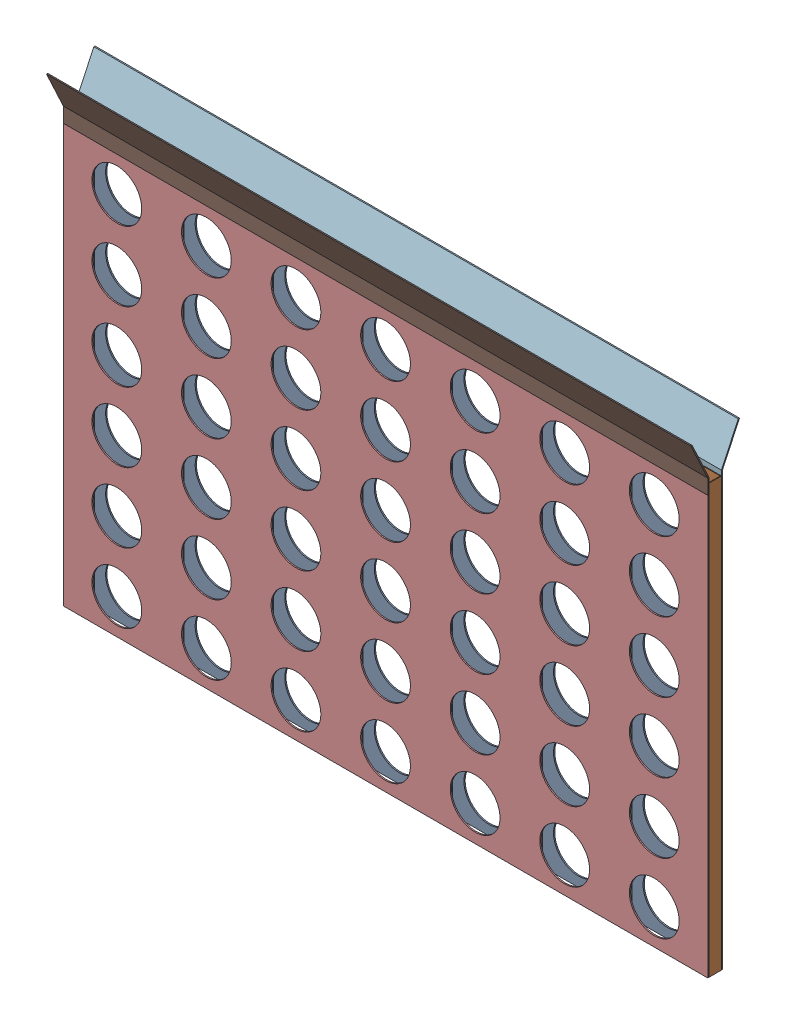
SolidWorks assembly checkerboard, configuration Default. Lengths in mm.
Overall size (3289.3 2393.96 247.95).
12 component instances, 3 part files, 0 mates.
Components (placement in the parent):
- Checkerboard_1-1: Checkerboard_1 [Default] at (-1824.7092 893.8456 -37.6809) size (3289.3 2133.6 6.35)
- slot seperator-1: slot seperator [Default] at (1420.1408 893.8456 0.4191) x (1 0 0) z (0 1 0) size (88.9 63.5 2184.4)
- slot seperator-2: slot seperator [Default] at (962.9408 893.8456 0.4191) x (1 0 0) z (0 1 0) size (88.9 63.5 2184.4)
- slot seperator-3: slot seperator [Default] at (505.7408 893.8456 0.4191) x (1 0 0) z (0 1 0) size (88.9 63.5 2184.4)
- slot seperator-4: slot seperator [Default] at (48.5408 893.8456 0.4191) x (1 0 0) z (0 1 0) size (88.9 63.5 2184.4)
- slot seperator-5: slot seperator [Default] at (-408.6592 893.8456 0.4191) x (1 0 0) z (0 1 0) size (88.9 63.5 2184.4)
- slot seperator-6: slot seperator [Default] at (-865.8592 893.8456 0.4191) x (1 0 0) z (0 1 0) size (88.9 63.5 2184.4)
- slot seperator-7: slot seperator [Default] at (-1323.0592 893.8456 0.4191) x (1 0 0) z (0 1 0) size (88.9 63.5 2184.4)
- slot seperator-8: slot seperator [Default] at (-1780.2592 893.8456 0.4191) x (1 0 0) z (0 1 0) size (88.9 63.5 2184.4)
- Checkerboard_1-2: Checkerboard_1 [Default] at (-1824.7092 893.8456 32.1691) size (3289.3 2133.6 6.35)
- funnel-1: funnel [Default] at (-1824.7092 3103.6456 32.1691) size (3289.3 260.36 92.23)
- funnel-2: funnel [Default] at (1464.5908 3103.6456 -31.3309) x (-1 0 0) z (0 0 -1) size (3289.3 260.36 92.23)
